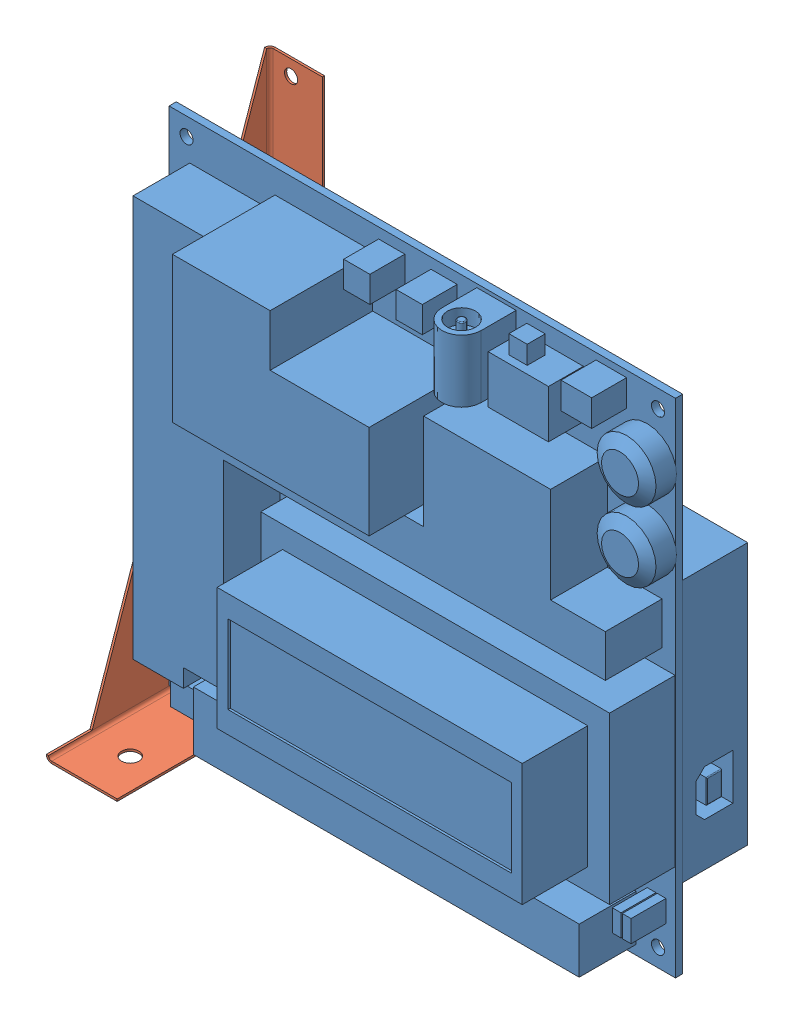
SolidWorks assembly TINAHAssembly, configuration Default. Lengths in mm.
Overall size (117.59 117.14 54.44).
2 component instances, 2 part files, 2 mates.
Components (placement in the parent):
- Tinah Board representation-1: Tinah Board representation [Default] at (43.1 59.1366 21.5558) x (-1 0 0) z (0 1 0) size (116.25 54.15 115)
- TINAHHolder2-1: TINAHHolder2 [Default] at origin size (16.24 116.5 51.24)
Mates (geometry in assembly coordinates):
- Concentric1: concentric: cylinder of Tinah Board representation-1 through (-10.9 112.5366 23.2058) axis (0 0 -1) radius 1.5; circle of TINAHHolder2-1
- Parallel1: parallel: plane of Tinah Board representation-1 through (101.1 116.6366 23.2058) normal (0 1 0); plane of TINAHHolder2-1 through (-3.7366 116 -1.2366) normal (0 1 0)
